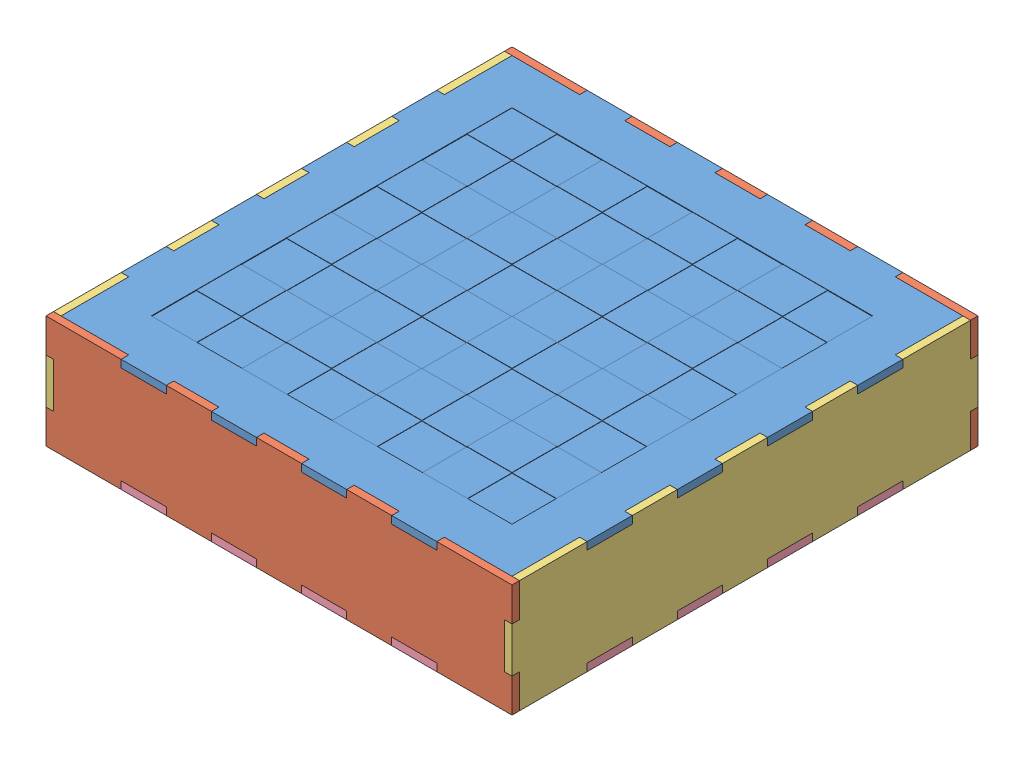
SolidWorks assembly CHESS_BOX, configuration Défaut. Lengths in mm.
Overall size (393.7 95.25 393.7).
6 component instances, 4 part files, 21 mates.
Components (placement in the parent):
- TOP_BOX-1: TOP_BOX [Défaut] at origin size (393.7 6.35 393.7)
- BOX_SIDE_FRONT-1: BOX_SIDE_FRONT [Défaut] at (0 -41.275 190.5) x (1 0 0) z (0 -1 0) size (393.7 6.35 95.25)
- BOX_SIDE_FRONT-2: BOX_SIDE_FRONT [Défaut] at (0 -41.275 -196.85) x (1 0 0) z (0 -1 0) size (393.7 6.35 95.25)
- BOX_SIDE_LEFT_RIGTH-1: BOX_SIDE_LEFT_RIGTH [Défaut] at (-190.5 -41.275 0) x (0 0 1) z (0 -1 0) size (393.7 6.35 95.25)
- BOX_SIDE_LEFT_RIGTH-2: BOX_SIDE_LEFT_RIGTH [Défaut] at (190.5 -41.275 0) x (0 0 -1) z (0 -1 0) size (393.7 6.35 95.25)
- BOTTOM_BOX-1: BOTTOM_BOX [Défaut] at (0 -88.9 0) size (393.7 6.35 393.7)
Mates (geometry in assembly coordinates):
- Parallèle1: parallel anti-aligned: plane of TOP_BOX-1 through (0 0 0) normal (0 -1 0); plane of BOX_SIDE_FRONT-1 through (228.6 0 190.5) normal (0 1 0)
- Coïncidente1: coincident anti-aligned: plane of TOP_BOX-1 through (133.35 6.35 196.85) normal (1 0 0); plane of BOX_SIDE_FRONT-1 through (133.35 0 190.5) normal (-1 0 0)
- Coïncidente2: coincident anti-aligned: plane of TOP_BOX-1 through (0 0 0) normal (0 -1 0); plane of BOX_SIDE_FRONT-1 through (228.6 0 190.5) normal (0 1 0)
- Coïncidente3: coincident anti-aligned: plane of TOP_BOX-1 through (-190.5 6.35 190.5) normal (0 0 1); plane of BOX_SIDE_FRONT-1 through (0 -41.275 190.5) normal (0 0 -1)
- Parallèle3: parallel anti-aligned: plane of TOP_BOX-1 through (0 6.35 0) normal (0 1 0); plane of BOX_SIDE_FRONT-2 through (-196.85 -88.9 -190.5) normal (0 -1 0)
- Coïncidente4: coincident anti-aligned: plane of TOP_BOX-1 through (19.05 6.35 -196.85) normal (-1 0 0); plane of BOX_SIDE_FRONT-2 through (19.05 0 -196.85) normal (1 0 0)
- Coïncidente5: coincident anti-aligned: plane of TOP_BOX-1 through (0 0 0) normal (0 -1 0); plane of BOX_SIDE_FRONT-2 through (152.4 0 -196.85) normal (0 1 0)
- Coïncidente6: coincident anti-aligned: plane of TOP_BOX-1 through (-190.5 6.35 -190.5) normal (0 0 -1); plane of BOX_SIDE_FRONT-2 through (0 -41.275 -190.5) normal (0 0 1)
- Parallèle4: parallel aligned: plane of TOP_BOX-1 through (0 6.35 0) normal (0 1 0); plane of BOX_SIDE_LEFT_RIGTH-2 through (196.85 6.35 190.5) normal (0 1 0)
- Parallèle5: parallel aligned: plane of BOX_SIDE_FRONT-1 through (0 -41.275 196.85) normal (0 0 1); plane of BOX_SIDE_LEFT_RIGTH-2 through (190.5 -41.275 196.85) normal (0 0 1)
- Coïncidente7: coincident anti-aligned: plane of TOP_BOX-1 through (196.85 6.35 95.25) normal (0 0 -1); plane of BOX_SIDE_LEFT_RIGTH-2 through (196.85 0 95.25) normal (0 0 1)
- Coïncidente8: coincident anti-aligned: plane of BOX_SIDE_FRONT-1 through (190.5 -41.275 190.5) normal (1 0 0); plane of BOX_SIDE_LEFT_RIGTH-2 through (190.5 -41.275 0) normal (-1 0 0)
- Coïncidente9: coincident anti-aligned: plane of TOP_BOX-1 through (0 0 0) normal (0 -1 0); plane of BOX_SIDE_LEFT_RIGTH-2 through (190.5 0 228.6) normal (0 1 0)
- Parallèle6: parallel aligned: plane of BOX_SIDE_FRONT-1 through (0 -41.275 196.85) normal (0 0 1); plane of BOX_SIDE_LEFT_RIGTH-1 through (-190.5 -41.275 196.85) normal (0 0 1)
- Parallèle7: parallel aligned: plane of TOP_BOX-1 through (0 6.35 0) normal (0 1 0); plane of BOX_SIDE_LEFT_RIGTH-1 through (-196.85 6.35 -190.5) normal (0 1 0)
- Coïncidente10: coincident anti-aligned: plane of TOP_BOX-1 through (0 0 0) normal (0 -1 0); plane of BOX_SIDE_LEFT_RIGTH-1 through (-190.5 0 0) normal (0 1 0)
- Coïncidente11: coincident anti-aligned: plane of TOP_BOX-1 through (-190.5 6.35 190.5) normal (-1 0 0); plane of BOX_SIDE_LEFT_RIGTH-1 through (-190.5 -41.275 0) normal (1 0 0)
- Coïncidente12: coincident anti-aligned: plane of BOX_SIDE_FRONT-1 through (0 -41.275 190.5) normal (0 0 -1); plane of BOX_SIDE_LEFT_RIGTH-1 through (-196.85 6.35 190.5) normal (0 0 1)
- Coïncidente13: coincident: plane of BOX_SIDE_LEFT_RIGTH-2 through (196.85 -88.9 133.35) normal (0 0 -1); plane of BOTTOM_BOX-1 through (190.5 -82.55 133.35) normal (0 0 1)
- Coïncidente14: coincident: plane of BOX_SIDE_LEFT_RIGTH-2 through (190.5 -82.55 228.6) normal (0 -1 0); plane of BOTTOM_BOX-1 through (-6.35 -82.55 0) normal (0 1 0)
- Coïncidente15: coincident anti-aligned: plane of BOX_SIDE_FRONT-1 through (133.35 -82.55 190.5) normal (-1 0 0); plane of BOTTOM_BOX-1 through (127 -82.55 196.85) normal (1 0 0)
